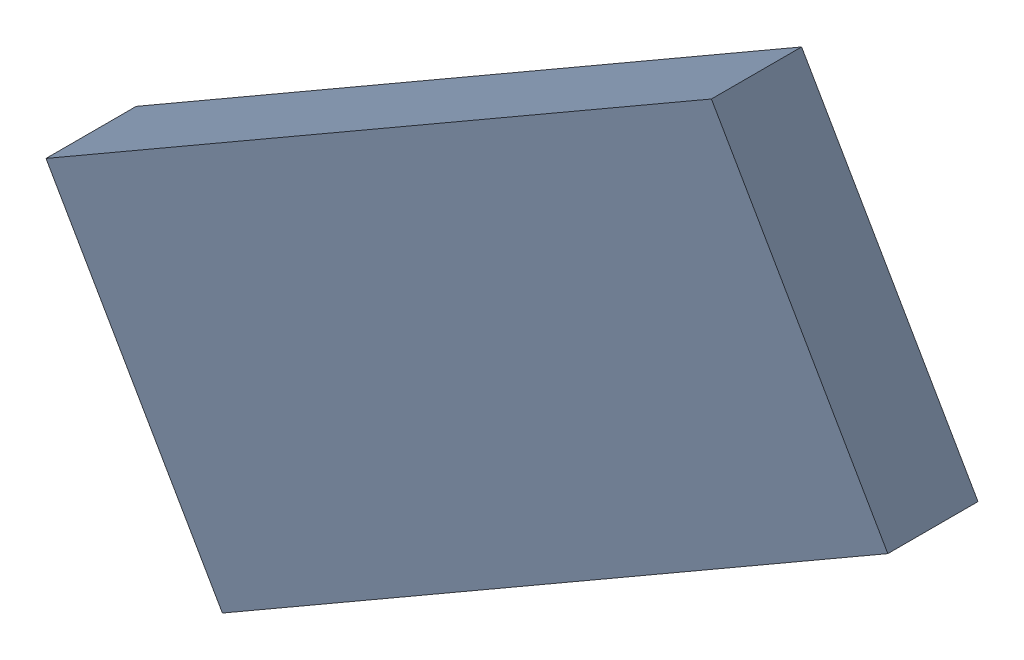
SolidWorks assembly TDA5340_TDA5, configuration Standard. Lengths in mm.
Overall size (10.74 8.8 1.15).
2 component instances, 1 part files, 0 mates.
Components (placement in the parent):
- 885544280-1: 885544280 [Standard] at (-41.9922 -27.6432 0.05) size (10.74 8.8 1.15)
  - Extruded_12-1: Extruded_12 [Standard] at origin size (10.74 8.8 1.15)
